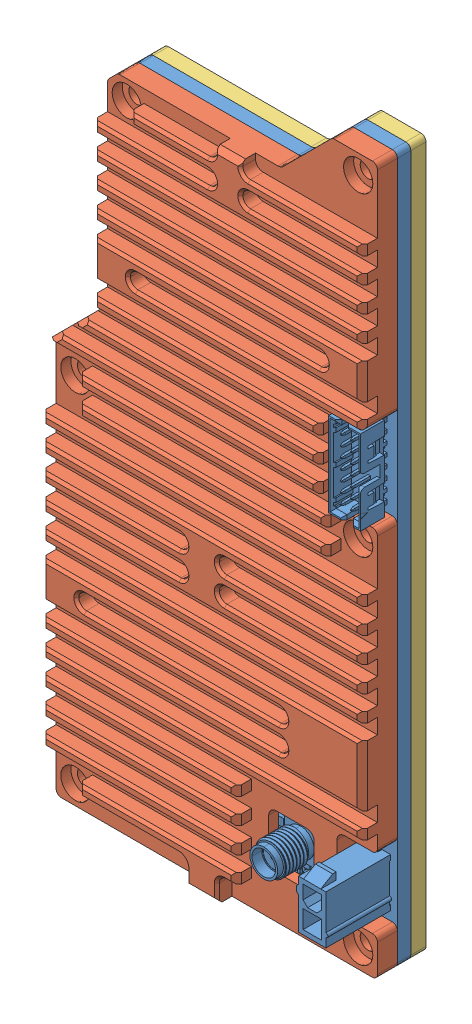
SolidWorks assembly Dboard_IF_TX-7_assembly, configuration Default. Lengths in mm.
Overall size (63.5 139.7 20.84).
10 component instances, 4 part files, 9 mates.
Components (placement in the parent):
- 2m_DBoard_TX-1: 2m_DBoard_TX [Default] at origin size (63.5 139.7 20.84)
- TX_case_top-1: TX_case_top [Default] at (128.74 50 0) x (1 0 0) z (0 -1 0) size (63.5 6.95 139.7)
- TX_case_bottom-1: TX_case_bottom [Default] at (128.74 50 -2.6463) x (1 0 0) z (0 -1 0) size (63.5 3 139.7)
- torx_socket_countersunk_flat_head_M3x10.step-1: torx_socket_countersunk_flat_head_M3x10.step [Default] at (165.57 175.73 -3.9963) x (-0.528098 -0.849183 0) z (0 0 -1) size (6 6 10)
- torx_socket_countersunk_flat_head_M3x10.step-2: torx_socket_countersunk_flat_head_M3x10.step [Default] at (142.71 149.69 -3.9963) x (-0.993338 -0.115237 0) z (0 0 -1) size (6 6 10)
- torx_socket_countersunk_flat_head_M3x10.step-3: torx_socket_countersunk_flat_head_M3x10.step [Default] at (132.55 88.74 -3.9963) x (-1 0 0) z (0 0 -1) size (6 6 10)
- torx_socket_countersunk_flat_head_M3x10.step-4: torx_socket_countersunk_flat_head_M3x10.step [Default] at (160.49 53.81 -3.9963) x (-1 0 0) z (0 0 -1) size (6 6 10)
- torx_socket_countersunk_flat_head_M3x10.step-5: torx_socket_countersunk_flat_head_M3x10.step [Default] at (188.43 88.74 -3.9963) x (-1 0 0) z (0 0 -1) size (6 6 10)
- torx_socket_countersunk_flat_head_M3x10.step-6: torx_socket_countersunk_flat_head_M3x10.step [Default] at (160.49 106 -3.9963) x (-1 0 0) z (0 0 -1) size (6 6 10)
- torx_socket_countersunk_flat_head_M3x10.step-7: torx_socket_countersunk_flat_head_M3x10.step [Default] at (188.43 154.77 -3.9963) x (-0.96299 0.269538 0) z (0 0 -1) size (6 6 10)
Mates (geometry in assembly coordinates):
- Coincident1: coincident: plane of 2m_DBoard_TX-1 through (0 0 0) normal (0 0 1); plane of assembly through (0 0 0) normal (0 0 1)
- Coincident2: coincident: plane of 2m_DBoard_TX-1 through (0 0 0) normal (1 0 0); plane of assembly through (0 0 0) normal (1 0 0)
- Coincident3: coincident: plane of 2m_DBoard_TX-1 through (128.74 51 0) normal (0 0 1); plane of TX_case_top-1 through (191.24 188.7 0) normal (0 0 -1)
- Concentric1: concentric: cylinder of 2m_DBoard_TX-1 through (188.43 53.81 -2.6463) axis (0 0 -1) radius 1.6; cylinder of TX_case_top-1 through (188.43 53.81 3.95) axis (0 0 1) radius 1.6
- Concentric2: concentric: cylinder of 2m_DBoard_TX-1 through (142.71 175.73 -2.6463) axis (0 0 -1) radius 1.6; cylinder of TX_case_top-1 through (142.71 175.73 3.95) axis (0 0 1) radius 1.6
- Coincident4: coincident: plane of 2m_DBoard_TX-1 through (128.74 51 -2.6463) normal (0 0 -1); plane of TX_case_bottom-1 through (191.24 188.7 -2.6463) normal (0 0 1)
- Concentric3: concentric: cylinder of 2m_DBoard_TX-1 through (188.43 185.89 -2.6463) axis (0 0 -1) radius 1.6; cylinder of TX_case_bottom-1 through (188.43 185.89 -5.6463) axis (0 0 -1) radius 1.6
- Concentric4: concentric: cylinder of 2m_DBoard_TX-1 through (132.55 53.81 -2.6463) axis (0 0 -1) radius 1.6; cylinder of TX_case_bottom-1 through (132.55 53.81 -5.6463) axis (0 0 -1) radius 1.6
- Coincident6: coincident: plane of 2m_DBoard_TX-1 through (0 0 0) normal (0 1 0); plane of assembly through (0 0 0) normal (0 1 0)
